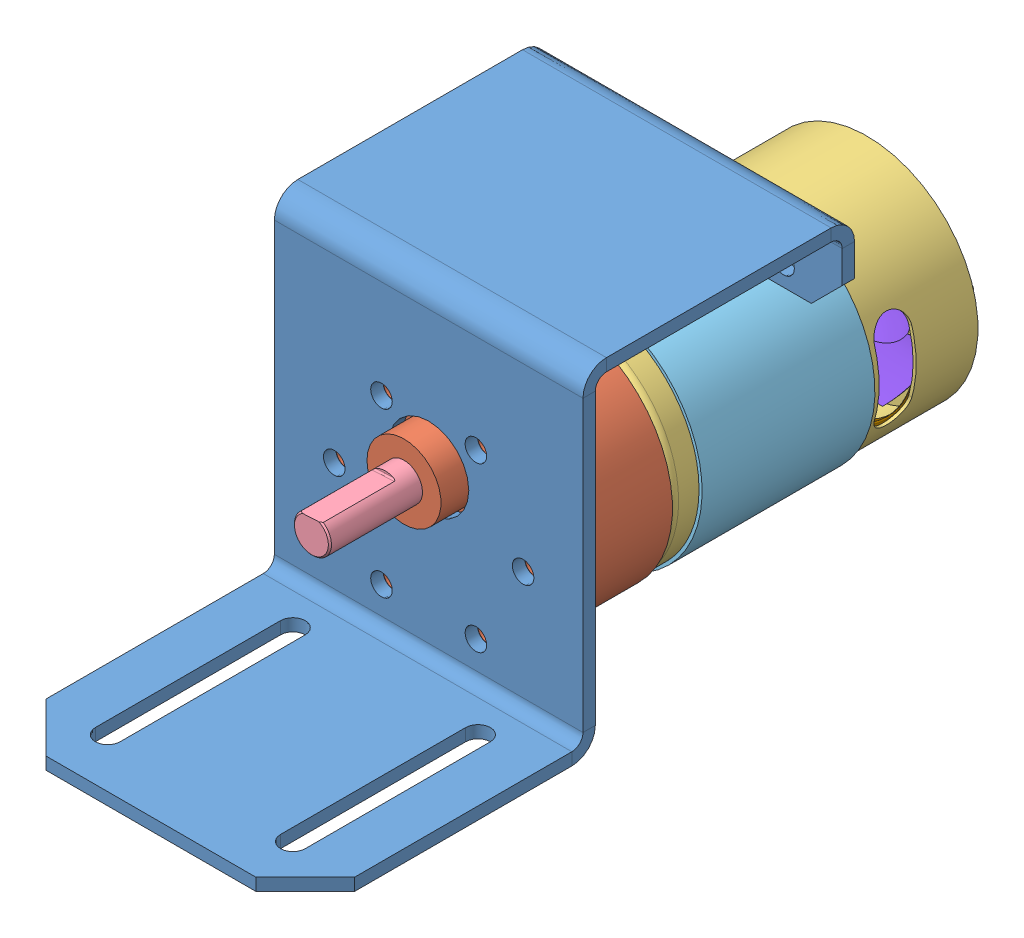
SolidWorks assembly Assem1, configuration Default. Lengths in mm.
Overall size (50 54.5 94.88).
13 component instances, 12 part files, 3 mates.
Components (placement in the parent):
- Part2-1: Part2 [Default] at (13.2024 34.6208 41.4032) size (50 54.5 89)
- Motor JGB37-545-1: Motor JGB37-545 [Predeterminado] at (25.5774 33.1208 -32.4718) size (37 37 94.88)
  - Reduction box body-1: Reduction box body [Default] at (-12.375 1.5 54.875) size (37 37 25)
  - Motor body-1: Motor body [Predeterminado] at (-12.375 1.5 4.875) size (36 36 52)
  - Shaft-1: Shaft [Predeterminado] at (-12.375 8.5 67.775) x (0.998724 0.050497 0) z (0 0 1) size (6 6 27.1)
  - Cover-1: Cover [Predeterminado] at (-12.375 1.5 22.075) size (37 36.74 28)
  - Rotor-1: Rotor [Predeterminado] at (-12.375 1.5 32.275) x (0.999981 -0.006201 0) z (0 0 1) size (26 25.6 60)
  - Magnets-1: Magnets [Default] at (-12.375 1.5 22.875) x (0 1 0) z (0 0 1) size (35 27.22 20)
  - Fan-1: Fan [Default] at (-12.375 1.5 12.975) x (0.995635 -0.093332 0) z (0.093332 0.995635 0) size (31.79 6.24 31.22)
  - Terminals-1: Terminals [Default] at (-12.375 1.5 5.375) x (1 0 0) z (0 0 -1) size (34 34 22.88)
  - Gear 1-1: Gear 1 [Default] at (-12.375 1.5 62.275) x (-0.006201 -0.999981 0) z (0.999981 -0.006201 0) size (5.97 2 5.97)
  - Gear 2-1: Gear 2 [Default] at (-12.375 -3.65 64.275) x (-0.919431 0.393252 0) z (-0.393252 -0.919431 0) size (20 8.6 20)
  - Gear 3-1: Gear 3 [Default] at (-12.375 8.5 66.275) x (0.050497 -0.998724 0) z (0.998724 0.050497 0) size (10 10 9.98)
Mates (geometry in assembly coordinates):
- Concentric1: concentric: cylinder of Part2-1 through (13.2024 41.6208 43.4032) axis (0 0 -1) radius 6.5; cylinder of Motor JGB37-545-1/Shaft-1 through (13.2024 41.6208 62.4032) axis (0 0 -1) radius 3
- Concentric2: concentric: cylinder of Part2-1 through (20.8524 47.871 43.4032) axis (0 0 -1) radius 1.75; cylinder of Motor JGB37-545-1/Reduction box body-1 through (20.8524 47.871 41.4032) axis (0 0 1) radius 1.7
- Coincident1: coincident anti-aligned: plane of Part2-1 through (13.2024 34.6208 41.4032) normal (0 0 -1); plane of Motor JGB37-545-1/Reduction box body-1 through (13.2024 34.6208 41.4032) normal (0 0 1)
